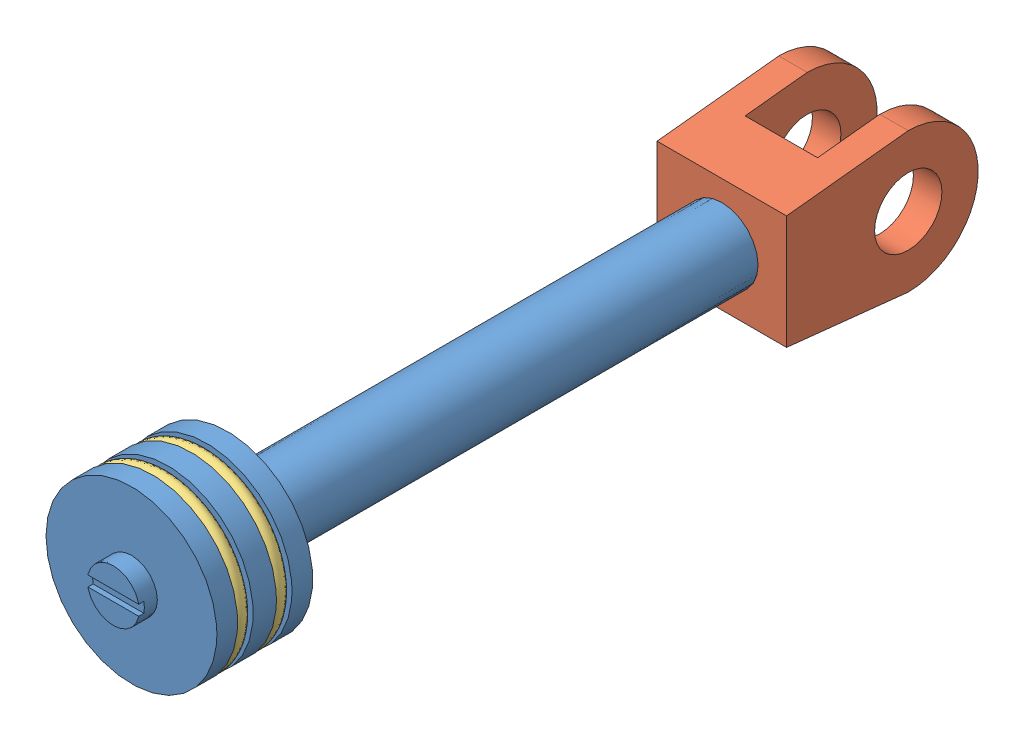
SolidWorks assembly Сборка поршня - МЛИ2.02.00, configuration По умолчанию. Lengths in mm.
Overall size (81.34 81.34 309).
4 component instances, 3 part files, 8 mates.
Components (placement in the parent):
- Поршень - МЛИ2.00.04-1: Поршень - МЛИ2.00.04 [По умолчанию] at origin size (66 66 263)
- Вилка - МЛИ2.00.05-1: Вилка - МЛИ2.00.05 [По умолчанию] at (25 0 -19) x (0 0 1) z (-1 0 0) size (74 54 50)
- Кольцо уплотнительное-1: Кольцо уплотнительное [По умолчанию] at (0 0 245.1) x (0 0 -1) z (0.983572 -0.180516 0) size (5.8 65.6 65.6)
- Кольцо уплотнительное-2: Кольцо уплотнительное [По умолчанию] at (0 0 230.1) x (0 0 1) z (-0.960016 -0.279944 0) size (5.8 65.6 65.6)
Mates (geometry in assembly coordinates):
- Концентричный1: concentric anti-aligned: cylinder of Поршень - МЛИ2.00.04-1 through (0 0 25) axis (0 0 -1) radius 11; cylinder of Вилка - МЛИ2.00.05-1 through (0 0 5) axis (0 0 1) radius 11
- Совпадение1: coincident anti-aligned: plane of Поршень - МЛИ2.00.04-1 through (0 0 28) normal (0 0 -1); plane of Вилка - МЛИ2.00.05-1 through (-25 22 28) normal (0 0 1)
- Совпадение2: coincident anti-aligned: line of Поршень - МЛИ2.00.04-1 through (0 0 216) axis (0 0 -1); line of Кольцо уплотнительное-1 through (0 0 226.5093) axis (0 0 1)
- Касательность2: tangent anti-aligned: plane of Поршень - МЛИ2.00.04-1 through (0 0 248) normal (0 0 -1); torus of Кольцо уплотнительное-1
- Совпадение3: coincident: axis of Кольцо уплотнительное-1 through (0 0 226.5093) axis (0 0 1); axis of Кольцо уплотнительное-2 through (0 0 248.6907) axis (0 0 -1)
- Касательность4: tangent anti-aligned: plane of Поршень - МЛИ2.00.04-1 through (0 0 233) normal (0 0 -1); torus of Кольцо уплотнительное-2
- Параллельность2: parallel: line of Поршень - МЛИ2.00.04-1 through (0 0 216) axis (0 0 -1); plane of Вилка - МЛИ2.00.05-1 through (-25 0 -19) normal (-1 0 0)
- Параллельность4: parallel aligned: plane of Вилка - МЛИ2.00.05-1 through (25 0 -19) normal (1 0 0)
